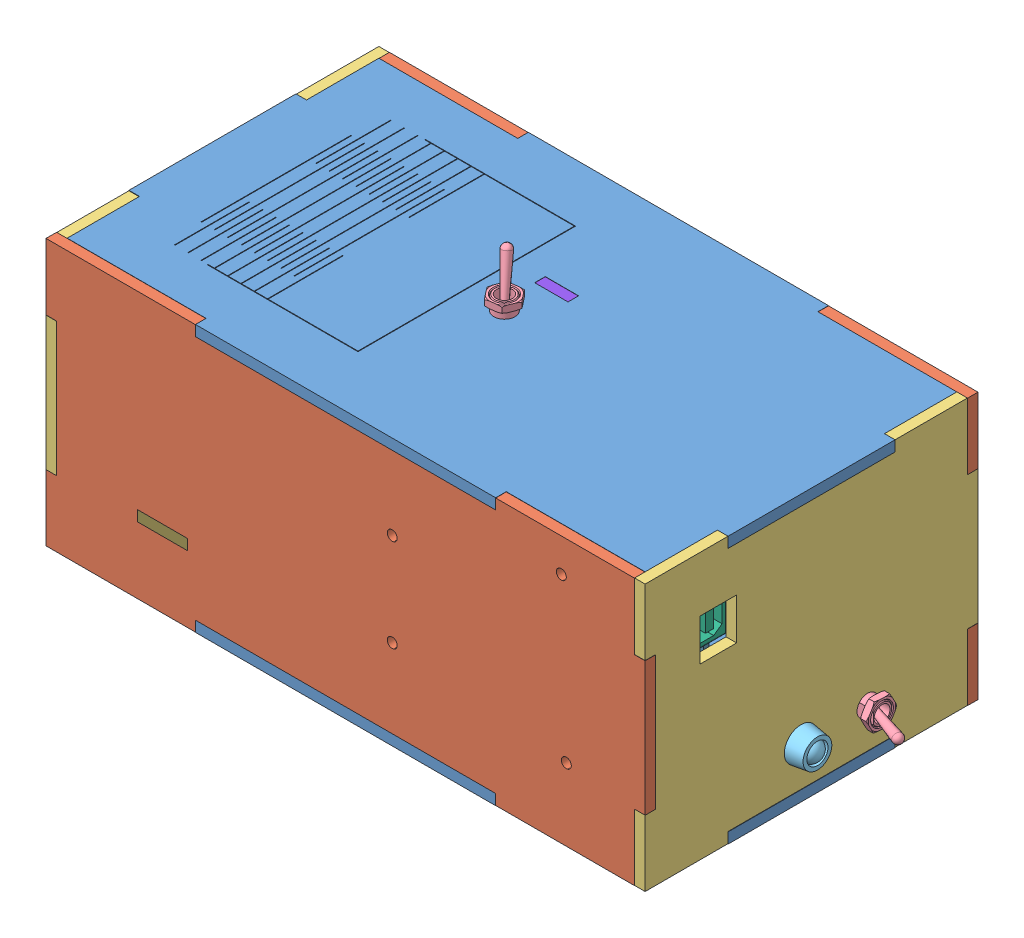
SolidWorks assembly Useless bobobobobobobobox, configuration Default. Lengths in mm.
Overall size (194.65 94.77 100).
25 component instances, 15 part files, 41 mates.
Components (placement in the parent):
- Useless boboboobx bottom-1: Useless boboboobx bottom [Default] at (73.7046 87.3412 139.2062) size (180 3.18 100)
- RightLeft,Useless bobobobobx-1: RightLeft,Useless bobobobobx [holes] at (73.7046 127.4012 186.0262) x (0 0 1) z (-1 0 0) size (3.18 80 180)
- FrontBack Useless boboboboboboox-1: FrontBack Useless boboboboboboox [holes] at (163.7046 127.4612 139.2062) x (0 0 1) z (-1 0 0) size (100 80 3.18)
- RightLeft,Useless bobobobobx-2: RightLeft,Useless bobobobobx [Default] at (73.7046 127.4012 92.3862) x (0 0 -1) z (1 0 0) size (3.18 80 180) (hidden)
- FrontBack Useless boboboboboboox-2: FrontBack Useless boboboboboboox [Default] at (-16.2954 127.3412 139.2062) x (0 0 -1) z (1 0 0) size (100 80 3.18)
- Useless boboboobx bottom-2: Useless boboboobx bottom [Top] at (73.7046 164.2812 139.2062) size (180 3.18 100)
- Panel Mount SPDT-1: Panel Mount SPDT [Default] at (71.4334 154.3712 139.2062) x (-0.788771 0 0.614687) z (-0.614687 0 -0.788771) size (8 31.74 12.7)
- Panel Mount LED-1: Panel Mount LED [Default] at (153.6496 102.4612 142.3862) x (0 0.844894 0.534934) z (0 0.534934 -0.844894) size (11.13 16 10.04)
- Panel Mount SPDT-43: Panel Mount SPDT [Default] at (150.6146 102.4612 122.3862) x (0 -0.999193 0.040176) z (0 0.040176 0.999193) size (8 31.74 12.7)
- ArduinoUno-1: ArduinoUno [Default] at (121.1246 133.2512 173.3262) x (-1 0 0) z (0 -1 0) size (74.8 12.1 53.3)
- 25x.5 Aluminum Hex Female Female Standoff-1: 25x.5 Aluminum Hex Female Female Standoff [Default] at (87.7246 114.2012 179.6762) size (6.35 8.06 12.7)
- 25x.5 Aluminum Hex Female Female Standoff-2: 25x.5 Aluminum Hex Female Female Standoff [Default] at (87.7246 142.1012 179.6762) size (6.35 8.06 12.7)
- 25x.5 Aluminum Hex Female Female Standoff-3: 25x.5 Aluminum Hex Female Female Standoff [Default] at (140.0246 109.1012 179.6762) size (6.35 8.06 12.7)
- 25x.5 Aluminum Hex Female Female Standoff-4: 25x.5 Aluminum Hex Female Female Standoff [Default] at (138.5246 157.4012 179.6762) size (6.35 8.06 12.7)
- Servo Holder-1: Servo Holder [Default] at (73.7046 127.4012 124.2062) size (30 80 3.18)
- Micro Servo SG92R 180-1: Micro Servo SG92R 180 [Valor predeterminado] at (73.3246 137.8766 122.0062) x (0 1 0) z (1 0 0) size (32 29 12)
- Arm with servo head-1: Arm with servo head [Default] at (27.5214 90.0988 107.973) x (-0.7971 0.603847 0) z (0.603847 0.7971 0) size (50.42 20 49.82)
  - Arm-1: Arm [Default] at (-14.582 29.9255 67.7314) size (50.42 20 49.82)
  - Micro Servo Horn Single Arm-10: Micro Servo Horn Single Arm [Default] at (-10.8295 27.3126 61.557) x (0.012527 0 0.999922) z (-0.999922 0 0.012527) size (19.74 4.23 7.24)
- Battery mount part with Battery mount-1: Battery mount part with Battery mount [Default] at (49.8802 164.6911 60.509) x (-1 0 0) z (0 0 1) size (40 22.49 100)
  - Battery mount part-1: Battery mount part [Default] at (31.1756 54.1099 78.6973) size (40 3.18 100)
  - 9V Battery Holder-1: 9V Battery Holder [Default] at (30.566 58.2899 77.1275) x (0 0 1) z (0 1 0) size (53.5 30 19.31)
- Prototyping Shield-Simple-2: Prototyping Shield-Simple [Default] at (100.9452 75.9678 196.2425) x (1 0 0) z (0 1 0) size (68 18.92 56)
  - Arduino Prototyping Shield-1: Arduino Prototyping Shield [Default] at (18.3696 35.0162 55.7334) size (68 18.92 56)
  - MiniBreadboard-Simple-1: MiniBreadboard-Simple [Default] at (16.6696 36.6462 55.7334) x (0 0 1) z (-1 0 0) size (34.6 8.15 45.6)
Mates (geometry in assembly coordinates):
- Coincident3: coincident aligned: line of Useless boboboobx bottom-1 through (28.6146 90.5212 189.2062) axis (1 0 0); line of RightLeft,Useless bobobobobx-1 through (28.6146 90.5212 189.2062) axis (1 0 0)
- Coincident8: coincident anti-aligned: line of FrontBack Useless boboboboboboox-1 through (160.5246 147.5512 89.2062) axis (0 -1 0); line of RightLeft,Useless bobobobobx-2 through (160.5246 107.3112 89.2062) axis (0 1 0)
- Coincident9: coincident: line of Useless boboboobx bottom-1 through (-13.1154 87.3412 92.3862) axis (0 1 0); plane of RightLeft,Useless bobobobobx-2 through (-13.1154 87.4012 112.5486) normal (-1 0 0)
- Coincident10: coincident anti-aligned: plane of Useless boboboobx bottom-1 through (73.7046 90.5212 139.2062) normal (0 1 0); plane of RightLeft,Useless bobobobobx-2 through (118.7946 90.5212 182.6202) normal (0 -1 0)
- Coincident12: coincident anti-aligned: line of RightLeft,Useless bobobobobx-1 through (-13.1154 107.3112 189.2062) axis (0 1 0); line of FrontBack Useless boboboboboboox-2 through (-13.1154 147.4312 189.2062) axis (0 -1 0)
- Coincident14: coincident aligned: line of RightLeft,Useless bobobobobx-1 through (28.6146 164.2812 189.2062) axis (1 0 0); line of Useless boboboobx bottom-2 through (28.6146 164.2812 189.2062) axis (1 0 0)
- Coincident15: coincident aligned: line of FrontBack Useless boboboboboboox-1 through (163.7046 164.2812 164.2962) axis (0 0 -1); line of Useless boboboobx bottom-2 through (163.7046 164.2812 164.2962) axis (0 0 -1)
- Concentric1: concentric anti-aligned: cylinder of Useless boboboobx bottom-2 through (71.4334 155.2868 139.2062) axis (0 1 0) radius 3.18; cylinder of Panel Mount SPDT-1 through (71.4334 171.8012 139.2062) axis (0 -1 0) radius 3.175
- Coincident16: coincident anti-aligned: plane of Useless boboboobx bottom-2 through (73.7046 164.2812 139.2062) normal (0 -1 0); plane of Panel Mount SPDT-1 through (71.4334 164.2812 139.2062) normal (0 1 0)
- Coincident18: coincident anti-aligned: plane of FrontBack Useless boboboboboboox-1 through (160.5246 127.4612 139.2062) normal (-1 0 0); plane of Panel Mount LED-1 through (160.5246 102.4612 142.3862) normal (1 0 0)
- Coincident19: coincident anti-aligned: plane of FrontBack Useless boboboboboboox-1 through (160.5246 127.4612 139.2062) normal (-1 0 0); plane of Panel Mount SPDT-43 through (160.5246 102.4612 122.3862) normal (1 0 0)
- Concentric4: concentric anti-aligned: cylinder of FrontBack Useless boboboboboboox-1 through (149.3947 102.4612 142.3862) axis (1 0 0) radius 3.935; cylinder of Panel Mount LED-1 through (153.6496 102.4612 142.3862) axis (-1 0 0) radius 3.937
- Concentric5: concentric anti-aligned: cylinder of FrontBack Useless boboboboboboox-1 through (149.3947 102.4612 122.3862) axis (1 0 0) radius 3.18; cylinder of Panel Mount SPDT-43 through (168.0446 102.4612 122.3862) axis (-1 0 0) radius 3.175
- Concentric8: concentric aligned: cylinder of RightLeft,Useless bobobobobx-1 through (138.5246 157.4012 181.7836) axis (0 0 1) radius 1.5; cylinder of ArduinoUno-1 through (138.5246 157.4012 171.7262) axis (0 0 1) radius 1.6
- Concentric9: concentric aligned: cylinder of RightLeft,Useless bobobobobx-1 through (87.7246 142.1012 181.7836) axis (0 0 1) radius 1.5; cylinder of ArduinoUno-1 through (87.7246 142.1012 171.7262) axis (0 0 1) radius 1.6
- Concentric10: concentric aligned: cylinder of RightLeft,Useless bobobobobx-1 through (138.5246 157.4012 181.7836) axis (0 0 1) radius 1.5; cylinder of 25x.5 Aluminum Hex Female Female Standoff-4 through (138.5246 157.4012 186.0262) axis (0 0 1) radius 1.0287
- Coincident27: coincident anti-aligned: plane of RightLeft,Useless bobobobobx-1 through (73.7046 127.4012 186.0262) normal (0 0 -1); plane of 25x.5 Aluminum Hex Female Female Standoff-4 through (138.5246 157.4012 186.0262) normal (0 0 1)
- Concentric11: concentric aligned: cylinder of RightLeft,Useless bobobobobx-1 through (140.0246 109.1012 181.7836) axis (0 0 1) radius 1.5; cylinder of 25x.5 Aluminum Hex Female Female Standoff-3 through (140.0246 109.1012 186.0262) axis (0 0 1) radius 1.0287
- Coincident28: coincident anti-aligned: plane of RightLeft,Useless bobobobobx-1 through (73.7046 127.4012 186.0262) normal (0 0 -1); plane of 25x.5 Aluminum Hex Female Female Standoff-3 through (140.0246 109.1012 186.0262) normal (0 0 1)
- Concentric12: concentric aligned: cylinder of RightLeft,Useless bobobobobx-1 through (87.7246 114.2012 181.7836) axis (0 0 1) radius 1.5; cylinder of 25x.5 Aluminum Hex Female Female Standoff-1 through (87.7246 114.2012 186.0262) axis (0 0 1) radius 1.0287
- Coincident29: coincident anti-aligned: plane of RightLeft,Useless bobobobobx-1 through (73.7046 127.4012 186.0262) normal (0 0 -1); plane of 25x.5 Aluminum Hex Female Female Standoff-1 through (87.7246 114.2012 186.0262) normal (0 0 1)
- Concentric14: concentric aligned: cylinder of RightLeft,Useless bobobobobx-1 through (87.7246 142.1012 181.7836) axis (0 0 1) radius 1.5; cylinder of 25x.5 Aluminum Hex Female Female Standoff-2 through (87.7246 142.1012 186.0262) axis (0 0 1) radius 1.0287
- Coincident30: coincident anti-aligned: plane of RightLeft,Useless bobobobobx-1 through (73.7046 127.4012 186.0262) normal (0 0 -1); plane of 25x.5 Aluminum Hex Female Female Standoff-2 through (87.7246 142.1012 186.0262) normal (0 0 1)
- Coincident31: coincident anti-aligned: plane of ArduinoUno-1 through (88.1246 159.9012 173.3262) normal (0 0 1); plane of 25x.5 Aluminum Hex Female Female Standoff-3 through (140.0246 109.1012 173.3262) normal (0 0 -1)
- Coincident35: coincident anti-aligned: plane of Useless boboboobx bottom-2 through (73.7046 164.2812 139.2062) normal (0 -1 0); plane of Servo Holder-1 through (78.7046 164.2812 113.7308) normal (0 1 0)
- Coincident36: coincident anti-aligned: plane of Useless boboboobx bottom-2 through (78.7046 153.7878 127.3862) normal (-1 0 0); plane of Servo Holder-1 through (78.7046 167.4012 113.7308) normal (1 0 0)
- Coincident38: coincident anti-aligned: plane of Useless boboboobx bottom-2 through (68.7046 153.7878 124.2062) normal (0 0 1); plane of Servo Holder-1 through (73.7046 127.4012 124.2062) normal (0 0 -1)
- Concentric16: concentric aligned: cylinder of Micro Servo SG92R 180-1 through (73.3246 132.6266 135.0062) axis (0 0 -1) radius 2.25; cylinder of Arm with servo head-1/Micro Servo Horn Single Arm-10 through (73.3246 132.6266 135.0062) axis (0 0 -1) radius 2.286
- Coincident45: coincident anti-aligned: plane of Micro Servo SG92R 180-1 through (73.3246 132.6266 135.0062) normal (0 0 1); plane of Arm with servo head-1/Micro Servo Horn Single Arm-10 through (73.3246 132.6266 135.0062) normal (0 0 -1)
- Coincident49: coincident aligned: line of RightLeft,Useless bobobobobx-1 through (26.2046 107.4012 189.2062) axis (-1 0 0); line of Battery mount part with Battery mount-1/Battery mount part-1 through (26.2046 107.4012 189.2062) axis (-1 0 0)
- Coincident50: coincident anti-aligned: plane of RightLeft,Useless bobobobobx-1 through (26.2046 110.5812 189.2062) normal (-1 0 0); plane of Battery mount part with Battery mount-1/Battery mount part-1 through (26.2046 110.5812 189.2062) normal (1 0 0)
- Coincident51: coincident aligned: line of RightLeft,Useless bobobobobx-2 through (11.2046 107.4012 89.2062) axis (1 0 0); line of Battery mount part with Battery mount-1/Battery mount part-1 through (11.2046 107.4012 89.2062) axis (1 0 0)
- Parallel1: parallel aligned: line of FrontBack Useless boboboboboboox-2 through (-16.2954 164.1612 114.1162) axis (0 0 1); line of Useless boboboobx bottom-2 through (-16.2954 164.2812 114.1162) axis (0 0 1)
- Parallel2: parallel aligned: line of RightLeft,Useless bobobobobx-2 through (-16.2954 107.3112 92.3862) axis (0 1 0); line of FrontBack Useless boboboboboboox-2 through (-16.2954 107.2512 92.3862) axis (0 1 0)
- Coincident54: coincident aligned: line of Useless boboboobx bottom-1 through (-13.1154 87.3412 114.1162) axis (0 0 -1); line of FrontBack Useless boboboboboboox-2 through (-13.1154 87.3412 114.1162) axis (0 0 -1)
- Coincident55: coincident anti-aligned: plane of ArduinoUno-1 through (120.7248 108.5012 163.7262) normal (-1 0 0); plane of Prototyping Shield-Simple-2/Arduino Prototyping Shield-1 through (120.7248 109.2012 169.9762) normal (1 0 0)
- Coincident56: coincident anti-aligned: plane of ArduinoUno-1 through (130.6248 157.0012 163.7262) normal (0 1 0); plane of Prototyping Shield-Simple-2/Arduino Prototyping Shield-1 through (129.3248 157.0012 169.9762) normal (0 -1 0)
- Coincident57: coincident anti-aligned: plane of ArduinoUno-1 through (160.3246 138.9012 161.2262) normal (0 0 -1); plane of Prototyping Shield-Simple-2/Arduino Prototyping Shield-1 through (153.3148 159.7012 161.2262) normal (0 0 1)
- Parallel5: parallel anti-aligned: plane of Servo Holder-1 through (73.7046 127.4012 124.2062) normal (0 0 -1); plane of Micro Servo SG92R 180-1 through (73.3246 151.5016 124.0062) normal (0 0 1)
- Coincident63: coincident: line of Servo Holder-1 through (67.3246 126.0352 124.2062) axis (0 1 0); plane of Micro Servo SG92R 180-1 through (67.3246 126.6266 106.0062) normal (-1 0 0)
- Coincident64: coincident anti-aligned: line of Servo Holder-1 through (67.3246 149.1266 124.2062) axis (1 0 0); line of Micro Servo SG92R 180-1 through (79.1246 149.1266 124.2062) axis (-1 0 0)
